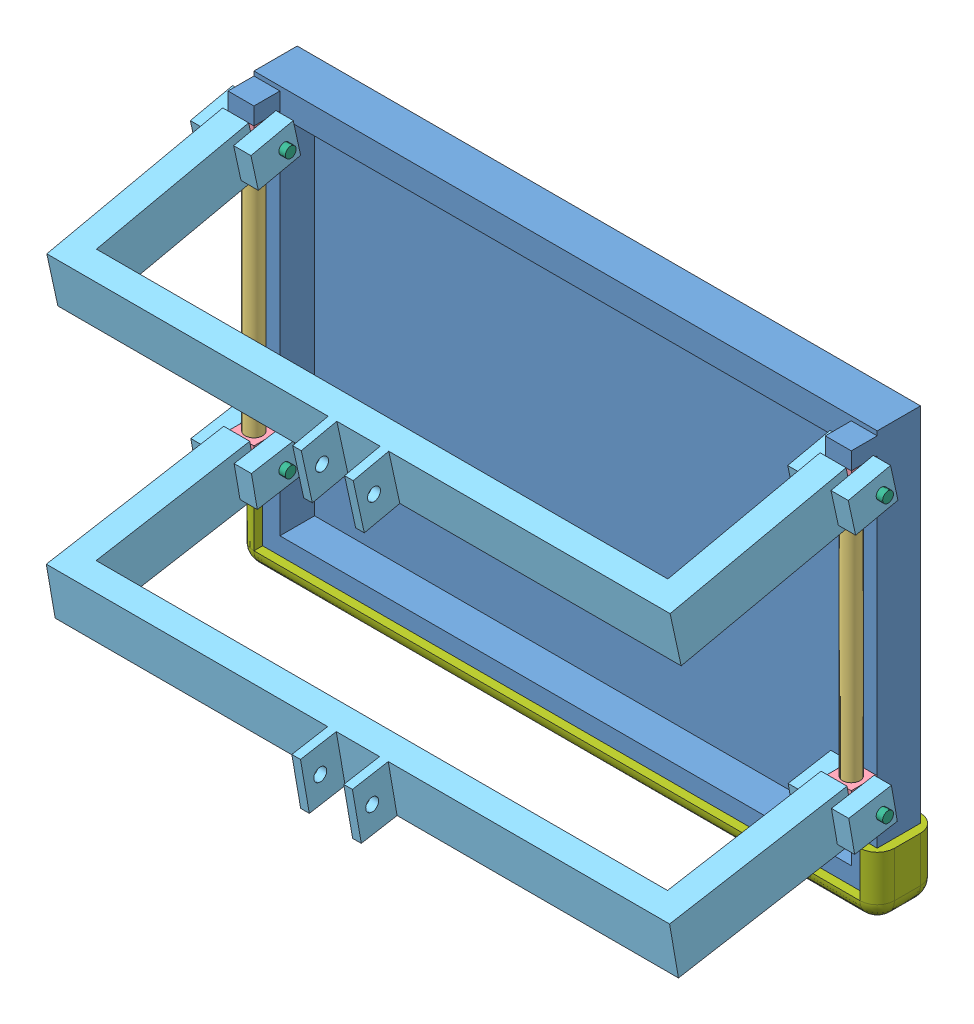
SolidWorks assembly Basketball.Hoop.Rim.Hinges, configuration Default. Lengths in mm.
Overall size (1968.5 1244.6 1416.55).
15 component instances, 7 part files, 32 mates.
Components (placement in the parent):
- BackBoard-1: BackBoard [Default] at (-72.0337 891.7241 1844.5519) size (1828.8 1219.2 203.2)
- Rim-1: Rim [Default] at (842.3663 1120.213 1497.9484) x (-1 0 0) z (0 0 -1) size (457.2 146.36 575.2)
- BackBoard.Pipe-1: BackBoard.Pipe [Default] at (-33.9337 1133.0241 2009.6519) size (50.8 914.4 50.8)
- BackBoard.Hinges-5: BackBoard.Hinges [Default] at (4.1663 1945.8241 2047.7519) x (0 0 -1) z (1 0 0) size (76.2 101.6 76.2)
- BackBoard.Hinges-6: BackBoard.Hinges [Default] at (-72.0337 1133.0241 1971.5519) x (0 0 1) z (-1 0 0) size (76.2 101.6 76.2)
- BackBoard.Pipe-3: BackBoard.Pipe [Default] at (1718.6663 1133.0241 2009.6519) size (50.8 914.4 50.8)
- BackBoard.Hinges-7: BackBoard.Hinges [Default] at (1680.5663 1133.0241 1971.5519) x (0 0 1) z (-1 0 0) size (76.2 101.6 76.2)
- BackBoard.Hinges-8: BackBoard.Hinges [Default] at (1680.5663 1945.8241 1971.5519) x (0 0 1) z (-1 0 0) size (76.2 101.6 76.2)
- Post.HingeTo.BackBoard.Hinge-1: Post.HingeTo.BackBoard.Hinge [Default] at (753.4663 994.096 2659.939) x (1 0 0) z (0 0.985389 0.170319) size (1930.4 711.2 152.4)
- Post.HingeTo.BackBoard.Hinge-2: Post.HingeTo.BackBoard.Hinge [Default] at (753.4663 1778.664 2651.0281) x (1 0 0) z (0 0.977006 0.213211) size (1930.4 711.2 152.4)
- Pin.BackBoard.Hinge-1: Pin.BackBoard.Hinge [Default] at (1610.7163 1183.8241 2009.6519) x (0 0 -1) z (1 0 0) size (31.75 31.75 215.9)
- Pin.BackBoard.Hinge-2: Pin.BackBoard.Hinge [Default] at (74.0163 1183.8241 2009.6519) x (0 0 1) z (-1 0 0) size (31.75 31.75 215.9)
- Pin.BackBoard.Hinge-3: Pin.BackBoard.Hinge [Default] at (74.0163 1996.6241 2009.6519) x (0 0 1) z (-1 0 0) size (31.75 31.75 215.9)
- Pin.BackBoard.Hinge-4: Pin.BackBoard.Hinge [Default] at (1610.7163 1996.6241 2009.6519) x (0 0 -1) z (1 0 0) size (31.75 31.75 215.9)
- BackBoard.Bumper-1: BackBoard.Bumper [Default] at (-97.4337 866.3241 1819.1519) size (1879.6 184.15 177.8)
Mates (geometry in assembly coordinates):
- Coincident7: coincident anti-aligned: plane of BackBoard-1 through (-72.0337 891.7241 1844.5519) normal (0 0 -1); plane of Rim-1 through (778.8663 1139.263 1844.5519) normal (0 0 1)
- Width1: width aligned: plane of BackBoard-1 through (-72.0337 891.7241 1971.5519) normal (-1 0 0); plane of BackBoard-1 through (1756.7663 891.7241 1971.5519) normal (1 0 0); plane of Rim-1 through (778.8663 1139.263 1717.5519) normal (-1 0 0); plane of Rim-1 through (905.8663 1139.263 1844.5519) normal (1 0 0)
- Concentric7: concentric anti-aligned: cylinder of BackBoard.Pipe-1 through (-33.9337 2047.4241 2009.6519) axis (0 -1 0) radius 25.4; cylinder of BackBoard.Hinges-5 through (-33.9337 1933.8861 2009.6519) axis (0 1 0) radius 25.4
- Coincident15: coincident anti-aligned: cylinder of BackBoard.Pipe-1 through (-59.3337 1996.6241 2009.6519) axis (1 0 0) radius 6.35; circle of BackBoard.Hinges-5
- Concentric8: concentric anti-aligned: cylinder of BackBoard.Pipe-1 through (-33.9337 2047.4241 2009.6519) axis (0 -1 0) radius 25.4; cylinder of BackBoard.Hinges-6 through (-33.9337 1121.0861 2009.6519) axis (0 1 0) radius 25.4
- Concentric9: concentric anti-aligned: cylinder of BackBoard.Pipe-1 through (-59.3337 1183.8241 2009.6519) axis (1 0 0) radius 6.35; cylinder of BackBoard.Hinges-6 through (1.8803 1183.8241 2009.6519) axis (-1 0 0) radius 6.35
- Coincident16: coincident anti-aligned: plane of BackBoard-1 through (-72.0337 1133.0241 2047.7519) normal (0 1 0); plane of BackBoard.Hinges-6 through (-72.0337 1133.0241 1971.5519) normal (0 -1 0)
- Coincident17: coincident anti-aligned: plane of BackBoard-1 through (-72.0337 2047.4241 2047.7519) normal (0 -1 0); plane of BackBoard.Hinges-5 through (4.1663 2047.4241 2047.7519) normal (0 1 0)
- Coincident18: coincident anti-aligned: line of BackBoard-1 through (-72.0337 2047.4241 1971.5519) axis (1 0 0); line of BackBoard.Hinges-5 through (4.1663 2047.4241 1971.5519) axis (-1 0 0)
- Coincident19: coincident anti-aligned: line of BackBoard-1 through (-72.0337 1133.0241 1971.5519) axis (0 1 0); line of BackBoard.Hinges-5 through (-72.0337 2047.4241 1971.5519) axis (0 -1 0)
- Concentric10: concentric anti-aligned: cylinder of BackBoard.Pipe-3 through (1718.6663 2047.4241 2009.6519) axis (0 -1 0) radius 25.4; cylinder of BackBoard.Hinges-8 through (1718.6663 1933.8861 2009.6519) axis (0 1 0) radius 25.4
- Concentric11: concentric anti-aligned: cylinder of BackBoard.Pipe-3 through (1693.2663 1996.6241 2009.6519) axis (1 0 0) radius 6.35; cylinder of BackBoard.Hinges-8 through (1754.4803 1996.6241 2009.6519) axis (-1 0 0) radius 6.35
- Concentric12: concentric anti-aligned: cylinder of BackBoard.Pipe-3 through (1718.6663 2047.4241 2009.6519) axis (0 -1 0) radius 25.4; cylinder of BackBoard.Hinges-7 through (1718.6663 1121.0861 2009.6519) axis (0 1 0) radius 25.4
- Concentric13: concentric anti-aligned: cylinder of BackBoard.Pipe-3 through (1693.2663 1183.8241 2009.6519) axis (1 0 0) radius 6.35; cylinder of BackBoard.Hinges-7 through (1754.4803 1183.8241 2009.6519) axis (-1 0 0) radius 6.35
- Coincident20: coincident anti-aligned: plane of BackBoard-1 through (1680.5663 2047.4241 2047.7519) normal (0 -1 0); plane of BackBoard.Hinges-8 through (1680.5663 2047.4241 1971.5519) normal (0 1 0)
- Coincident21: coincident anti-aligned: line of BackBoard-1 through (1680.5663 2047.4241 1971.5519) axis (1 0 0); line of BackBoard.Hinges-8 through (1756.7663 2047.4241 1971.5519) axis (-1 0 0)
- Coincident22: coincident anti-aligned: line of BackBoard-1 through (1756.7663 1133.0241 1971.5519) axis (0 1 0); line of BackBoard.Hinges-8 through (1756.7663 2047.4241 1971.5519) axis (0 -1 0)
- Concentric14: concentric aligned: cylinder of BackBoard.Hinges-6 through (1.8803 1183.8241 2009.6519) axis (-1 0 0) radius 6.35; cylinder of Post.HingeTo.BackBoard.Hinge-1 through (83.1603 1183.8241 2009.6519) axis (-1 0 0) radius 6.35
- Coincident23: coincident anti-aligned: plane of BackBoard.Hinges-6 through (-72.0337 1234.6241 1971.5519) normal (-1 0 0); plane of Post.HingeTo.BackBoard.Hinge-1 through (-72.0337 1140.2554 1963.4564) normal (1 0 0)
- Coincident24: coincident anti-aligned: plane of BackBoard.Hinges-5 through (-72.0337 2047.4241 2047.7519) normal (-1 0 0); plane of Post.HingeTo.BackBoard.Hinge-2 through (-72.0337 1955.1155 1961.5968) normal (1 0 0)
- Concentric15: concentric anti-aligned: cylinder of BackBoard.Hinges-5 through (-69.7477 1996.6241 2009.6519) axis (1 0 0) radius 6.35; cylinder of Post.HingeTo.BackBoard.Hinge-2 through (83.1603 1996.6241 2009.6519) axis (-1 0 0) radius 6.35
- Concentric16: concentric anti-aligned: cylinder of Post.HingeTo.BackBoard.Hinge-2 through (83.1603 1996.6241 2009.6519) axis (-1 0 0) radius 6.35; cylinder of Pin.BackBoard.Hinge-3 through (-122.8337 1996.6241 2009.6519) axis (1 0 0) radius 6.35
- Coincident25: coincident anti-aligned: plane of Post.HingeTo.BackBoard.Hinge-2 through (-122.8337 1778.664 2651.0281) normal (-1 0 0); plane of Pin.BackBoard.Hinge-3 through (-122.8337 1996.6241 2009.6519) normal (1 0 0)
- Concentric17: concentric anti-aligned: cylinder of Post.HingeTo.BackBoard.Hinge-2 through (1601.5723 1996.6241 2009.6519) axis (1 0 0) radius 6.35; cylinder of Pin.BackBoard.Hinge-4 through (1807.5663 1996.6241 2009.6519) axis (-1 0 0) radius 6.35
- Coincident26: coincident anti-aligned: plane of Post.HingeTo.BackBoard.Hinge-2 through (1629.7663 1778.664 2651.0281) normal (-1 0 0); plane of Pin.BackBoard.Hinge-4 through (1629.7663 1996.6241 2009.6519) normal (1 0 0)
- Coincident27: coincident anti-aligned: circle of Post.HingeTo.BackBoard.Hinge-1; cylinder of Pin.BackBoard.Hinge-1 through (1807.5663 1183.8241 2009.6519) axis (-1 0 0) radius 6.35
- Coincident28: coincident anti-aligned: plane of Post.HingeTo.BackBoard.Hinge-1 through (1629.7663 994.096 2659.939) normal (-1 0 0); plane of Pin.BackBoard.Hinge-1 through (1629.7663 1183.8241 2009.6519) normal (1 0 0)
- Concentric18: concentric anti-aligned: cylinder of Post.HingeTo.BackBoard.Hinge-1 through (83.1603 1183.8241 2009.6519) axis (-1 0 0) radius 6.35; cylinder of Pin.BackBoard.Hinge-2 through (-122.8337 1183.8241 2009.6519) axis (1 0 0) radius 6.35
- Coincident29: coincident anti-aligned: plane of Post.HingeTo.BackBoard.Hinge-1 through (-122.8337 994.096 2659.939) normal (-1 0 0); plane of Pin.BackBoard.Hinge-2 through (-122.8337 1183.8241 2009.6519) normal (1 0 0)
- Coincident31: coincident anti-aligned: plane of BackBoard-1 through (-72.0337 891.7241 1971.5519) normal (-1 0 0); plane of BackBoard.Bumper-1 through (-72.0337 891.7241 1844.5519) normal (1 0 0)
- Coincident32: coincident anti-aligned: plane of BackBoard-1 through (-72.0337 891.7241 1971.5519) normal (0 -1 0); plane of BackBoard.Bumper-1 through (-97.4337 891.7241 1819.1519) normal (0 1 0)
- Coincident33: coincident anti-aligned: plane of BackBoard-1 through (-72.0337 891.7241 1844.5519) normal (0 0 -1); plane of BackBoard.Bumper-1 through (-72.0337 891.7241 1844.5519) normal (0 0 1)
